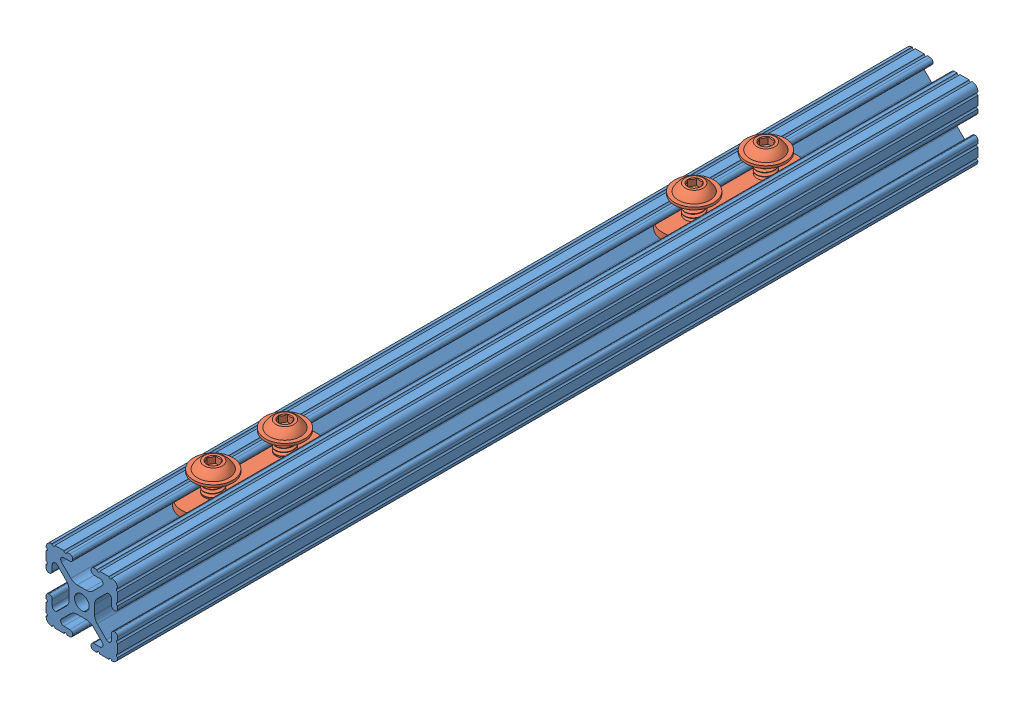
SolidWorks assembly Assem1, configuration Default. Lengths in mm.
Overall size (25.4 33.12 304.8).
3 component instances, 2 part files, 6 mates.
Components (placement in the parent):
- 1010-1: 1010 [Default] at (-122.0045 8.7755 210.8182) size (25.4 25.4 304.8)
- 47065T147_ALUMINUM T-SLOTTED FRAMING EXTRUSION-1: 47065T147_ALUMINUM T-SLOTTED FRAMING EXTRUSION [47065T147] at (-122.0045 25.6157 151.568) x (0 0 -1) z (1 0 0) size (47.62 16.7 13.87)
- 47065T147_ALUMINUM T-SLOTTED FRAMING EXTRUSION-2: 47065T147_ALUMINUM T-SLOTTED FRAMING EXTRUSION [47065T147] at (-122.0045 25.6157 -18.8279) x (0 0 1) z (-1 0 0) size (47.62 16.7 13.87)
Mates (geometry in assembly coordinates):
- Coincident1: coincident anti-aligned: plane of 1010-1 through (-126.292 19.2657 -93.9818) normal (0 -1 0); plane of 47065T147_ALUMINUM T-SLOTTED FRAMING EXTRUSION-1 through (-122.0045 19.2657 167.443) normal (0 1 0)
- Coincident7: coincident: moEndPointRef_w of 47065T147_ALUMINUM T-SLOTTED FRAMING EXTRUSION-1; plane of assembly
- Coincident8: coincident: moEndPointRef_w of 47065T147_ALUMINUM T-SLOTTED FRAMING EXTRUSION-1; plane of assembly
- Coincident11: coincident anti-aligned: plane of 1010-1 through (-117.7169 19.2657 -93.9818) normal (0 -1 0); plane of 47065T147_ALUMINUM T-SLOTTED FRAMING EXTRUSION-2 through (-122.0045 19.2657 -34.7029) normal (0 1 0)
- Coincident12: coincident: moEndPointRef_w of 47065T147_ALUMINUM T-SLOTTED FRAMING EXTRUSION-2; plane of assembly
- Coincident13: coincident: moEndPointRef_w of 47065T147_ALUMINUM T-SLOTTED FRAMING EXTRUSION-2; plane of assembly
